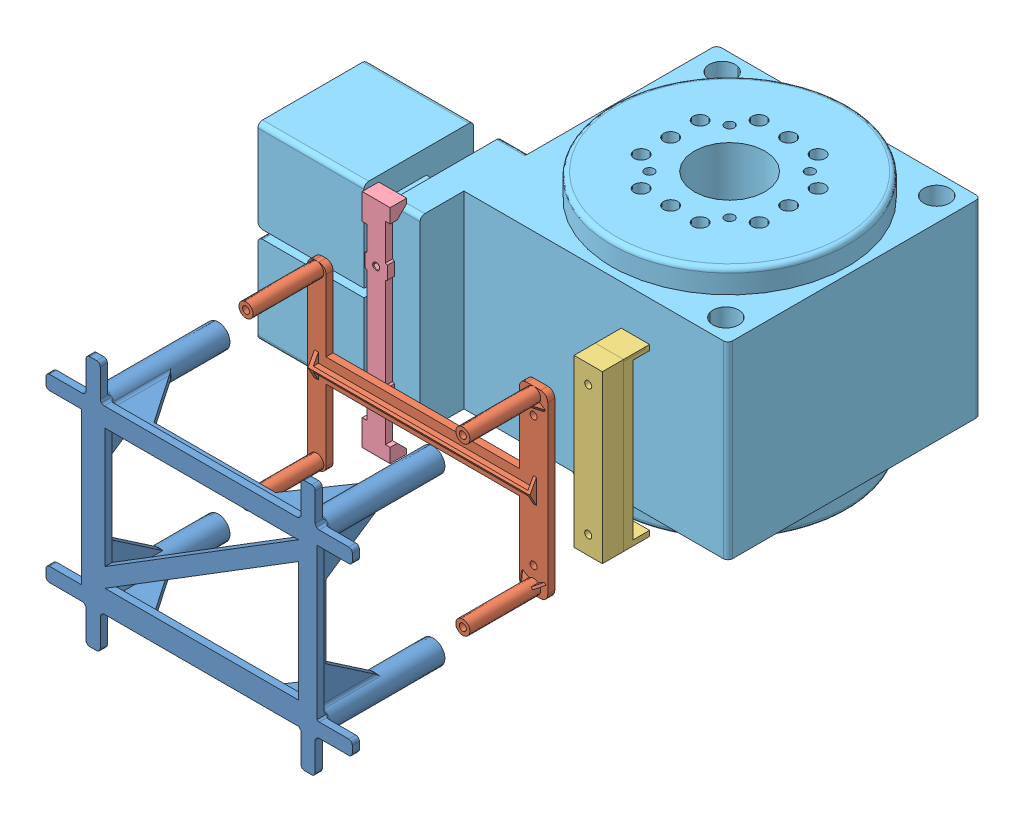
SolidWorks assembly 装配体1, configuration 默认. Lengths in mm.
Overall size (180.71 106.5 259.1).
5 component instances, 5 part files, 0 mates.
Components (placement in the parent):
- bottom_bottom-1: bottom_bottom [默认] at (-169.7204 -91.8866 330.5844) x (0 -1 0) z (1 0 0) size (106.5 53 129.85)
- bottom_middle-1: bottom_middle [默认] at (-97.5029 -89.2508 230.4233) x (0 -1 0) z (-1 0 0) size (76.5 33 101.85)
- BottomPlate-1: BottomPlate [默认] at (-90.4762 -129.2837 200.6945) x (0 1 0) z (-1 0 0) size (70.61 20 12.13)
- bottomv2-1: bottomv2 [默认] at (-195.4462 -37.3986 208.2558) x (0 -1 0) z (1 0 0) size (94 7 11.85)
- 零件_转台模型-1: 零件_转台模型 [默认] at (-125.8107 -124.2593 125.1316) size (180.71 100 125.72)
